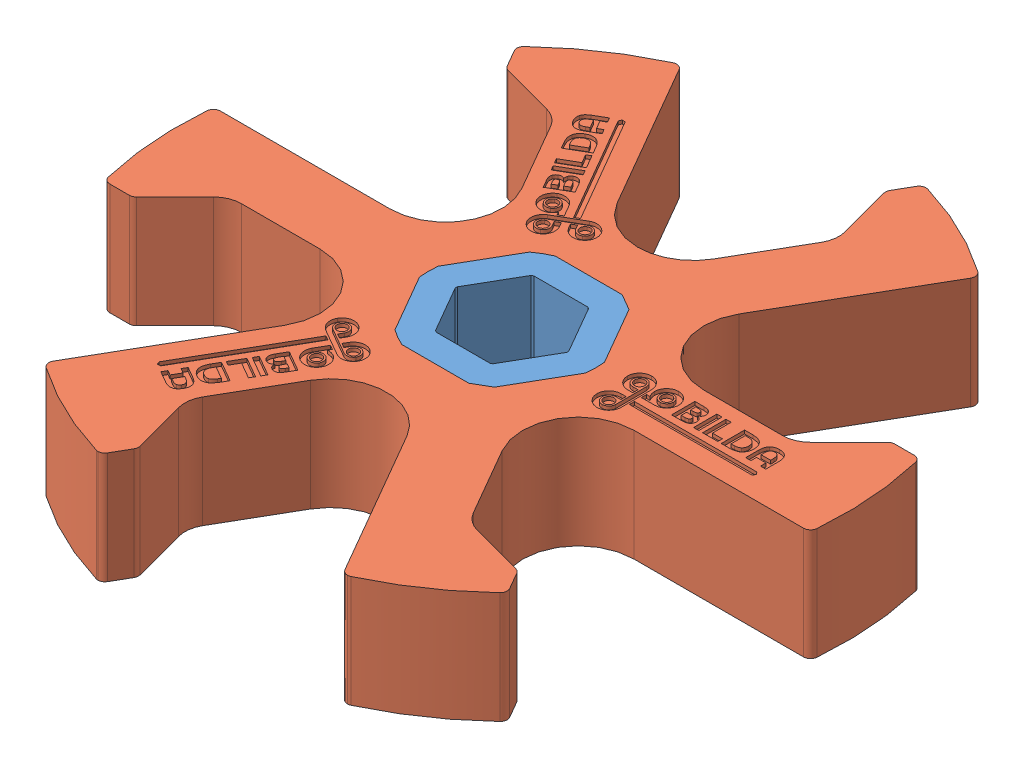
SolidWorks assembly 48mm Boot Wheel 3615-4008-0048, configuration Default. Lengths in mm.
Overall size (48 8 46.07).
2 component instances, 2 part files, 0 mates.
Components (placement in the parent):
- 3615-4008-0048 Core.STEP-1: 3615-4008-0048 Core.STEP [Default] at (-27.1858 0.0593 11.5877) size (12 8 11)
- 3615-4008-0048 Rubber.STEP-1: 3615-4008-0048 Rubber.STEP [Default] at (-27.1858 0.0593 11.5877) x (-1 0 0) z (0 0 -1) size (48 8 46.07)
